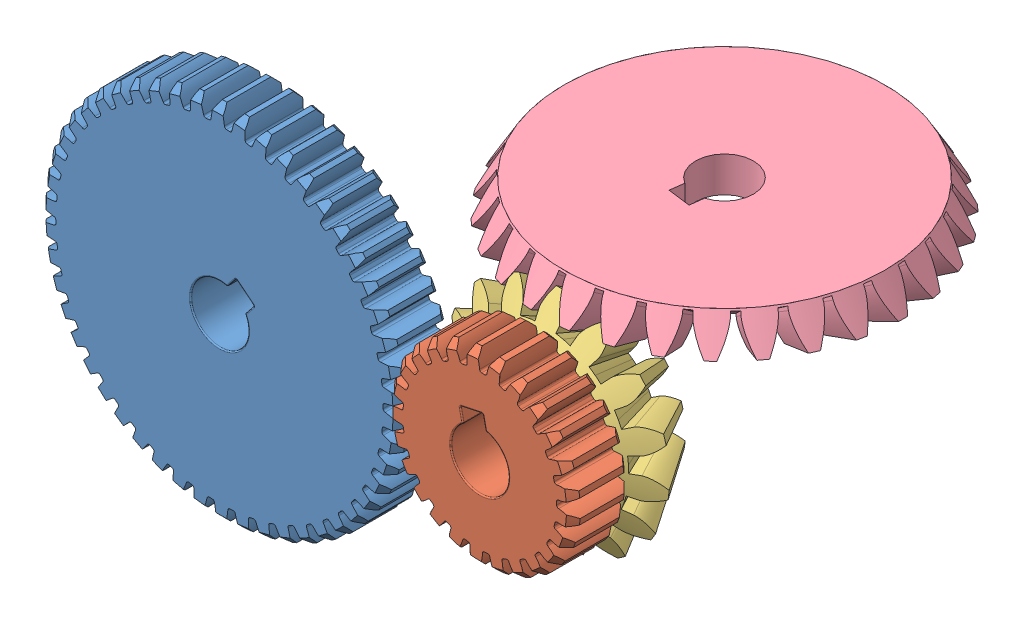
SolidWorks assembly ASSEMBLY Case Design Test, configuration Default. Lengths in mm.
Overall size (123.86 87.7 77.09).
4 component instances, 4 part files, 11 mates.
Components (placement in the parent):
- Secondary Big Spur Gear-1: Secondary Big Spur Gear [Default] x (0.777104 -0.629372 0) z (0 0 1) size (62.4 62.32 10)
- Main Spur Gear - Copy-1: Main Spur Gear - Copy [Default] at (44.996 0.5977 0) x (0.978656 0.205503 0) z (0 0 1) size (32.38 32.33 10)
- Secondary Bevel Gear-1: Secondary Bevel Gear [Default] at (44.996 0.5977 -7.4375) x (-0.303193 0.952929 0) z (-0.952929 -0.303193 0) size (38.4 11.9 38.26)
- Secondary Main Bevel Gear-1: Secondary Main Bevel Gear [Default] at (44.996 17.9182 -37.3154) x (-0.991453 0 -0.130461) z (-0.130461 0 0.991453) size (61.9 10.12 62)
Mates (geometry in assembly coordinates):
- Coincident1: coincident aligned: circle of Secondary Big Spur Gear-1
- Coincident2: coincident: point of Secondary Big Spur Gear-1; point of assembly
- Distance1: distance = 45 mm: point of Secondary Big Spur Gear-1; point of Main Spur Gear - Copy-1
- Coincident4: coincident aligned: plane of Secondary Big Spur Gear-1 through (0 0 0) normal (0 0 1); plane of Main Spur Gear - Copy-1 through (44.996 0.5977 0) normal (0 0 1)
- GearMate1: gear = 30 : 60 mm: circle of Secondary Big Spur Gear-1; circle of Main Spur Gear - Copy-1
- Concentric2: concentric: cylinder of Main Spur Gear - Copy-1 through (44.996 0.5977 -5) axis (0 0 1) radius 5; cylinder of Secondary Bevel Gear-1 through (44.996 0.5977 15) axis (0 0 -1) radius 5
- Coincident5: coincident anti-aligned: plane of Main Spur Gear - Copy-1 through (44.996 0.5977 -5) normal (0 0 -1); plane of Secondary Bevel Gear-1 through (44.996 0.5977 -5) normal (0 0 1)
- Perpendicular1: perpendicular: line of Secondary Bevel Gear-1 through (44.996 0.5977 -37.3154) axis (0 0 1); line of Secondary Main Bevel Gear-1 through (44.996 0.5977 -37.3154) axis (0 1 0)
- Coincident14: coincident: point of Secondary Bevel Gear-1; point of Secondary Main Bevel Gear-1
- GearMate2: gear = 60 : 34.5 mm: circle of Secondary Bevel Gear-1; circle of Secondary Main Bevel Gear-1
- Parallel4: parallel: line of Secondary Main Bevel Gear-1 through (44.996 0.5977 -37.3154) axis (0 1 0)
